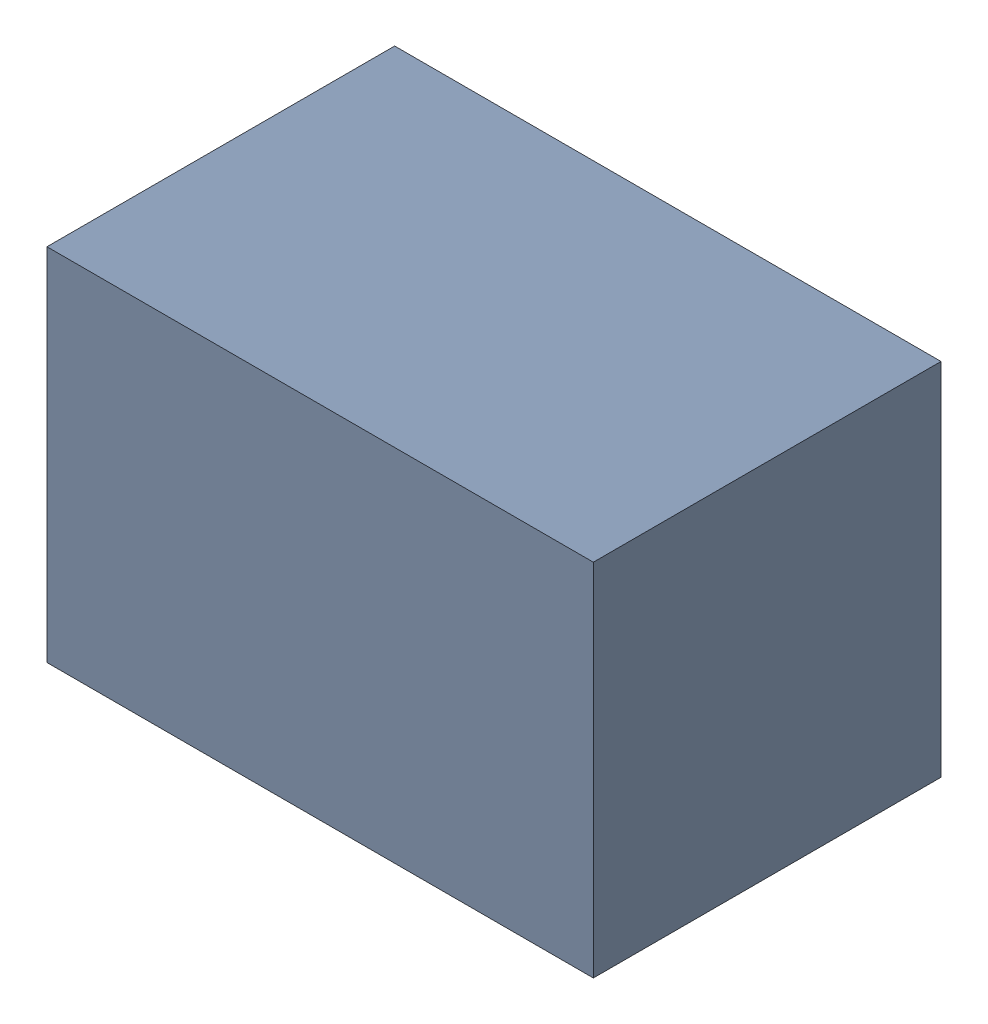
SolidWorks assembly D2, configuration Default. Lengths in mm.
Overall size (2.2 1.45 1.4).
2 component instances, 1 part files, 0 mates.
Components (placement in the parent):
- 959210024-1: 959210024 [Default] at (155.107 90.769 0) size (2.2 1.45 1.4)
  - Extruded-30-1: Extruded-30 [Default] at origin size (2.2 1.45 1.4)
